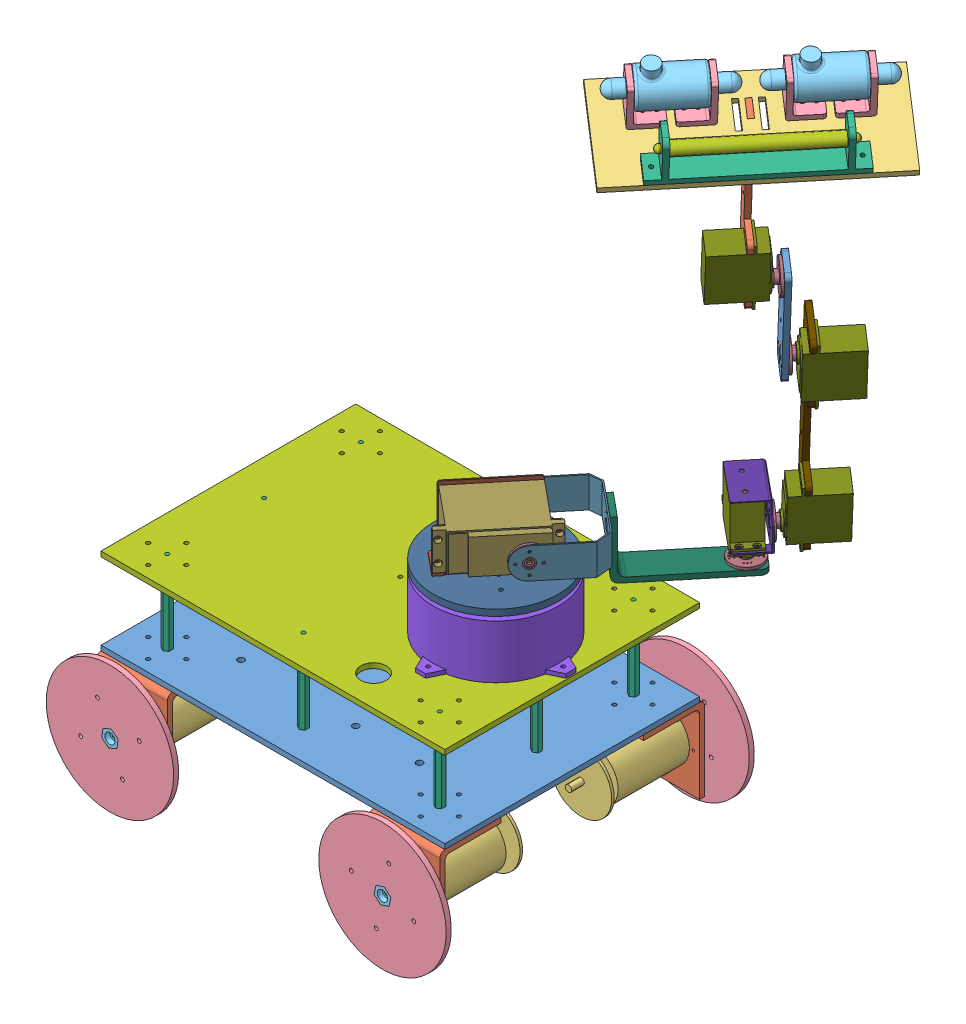
SolidWorks assembly robot_config3, configuration Default. Lengths in mm.
Overall size (478.46 609.43 282.21).
55 component instances, 25 part files, 138 mates.
Components (placement in the parent):
- base_odroid_down_fix-1: base_odroid_down_fix [Default] at (39.4639 122.941 229.7749) x (1 0 0) z (0 -1 0) size (270 200 4)
- link_motor_1_port-1: link_motor_1_port [Default] at (221.3654 112.3394 287.3354) x (0 0 -1) z (1 0 0) size (48 66 56)
- motor_dc_NISCA-1: motor_dc_NISCA [Default] at (244.2642 39.7289 313.6416) x (0 -1 0) z (0 0 -1) size (54 48 92)
- roda_shaft-1: roda_shaft [Default] at (185.8398 121.6563 330.6416) x (-0.980223 0.197896 0) z (0 0 1) size (100 100 4)
- shaft_adapter_5mm-1: shaft_adapter_5mm [Default] at (248.7954 72.9583 317.6416) x (0.980223 -0.197896 0) z (0 0 1) size (12 13.86 17)
- link_motor_1_port-2: link_motor_1_port [Default] at (221.3654 112.3394 139.9479) x (0 0 1) z (-1 0 0) size (48 66 56)
- motor_dc_NISCA-2: motor_dc_NISCA [Default] at (198.4666 39.7289 113.6416) x (0 -1 0) z (0 0 1) size (54 48 92)
- shaft_adapter_5mm-3: shaft_adapter_5mm [Default] at (238.0112 59.5291 109.6416) x (0.404857 -0.91438 0) z (0 0 -1) size (12 13.86 17)
- roda_shaft-2: roda_shaft [Default] at (222.1063 135.748 96.6416) x (0.589448 0.807807 0) z (0 0 -1) size (100 100 4)
- link_motor_1_port-5: link_motor_1_port [Default] at (7.3654 112.3394 287.3354) x (0 0 -1) z (1 0 0) size (48 66 56)
- motor_dc_NISCA-5: motor_dc_NISCA [Default] at (-15.5334 128.1531 313.6416) x (0 1 0) z (0 0 -1) size (54 48 92)
- roda_shaft-5: roda_shaft [Default] at (51.5287 56.8466 334.6416) x (0.393495 -0.919327 0) z (0 0 -1) size (100 100 4)
- shaft_adapter_5mm-6: shaft_adapter_5mm [Default] at (0.8367 112.7577 317.6416) x (-0.393495 0.919327 0) z (0 0 1) size (12 13.86 17)
- link_motor_1_port-6: link_motor_1_port [Default] at (7.3654 112.3394 139.9479) x (0 0 1) z (-1 0 0) size (48 66 56)
- motor_dc_NISCA-6: motor_dc_NISCA [Default] at (-15.5334 39.7289 113.6416) x (0 -1 0) z (0 0 1) size (54 48 92)
- roda_shaft-6: roda_shaft [Default] at (45.258 48.6046 96.6416) x (0.202799 -0.97922 0) z (0 0 -1) size (100 100 4)
- shaft_adapter_5mm-7: shaft_adapter_5mm [Default] at (36.6325 79.8838 109.6416) x (0.949429 -0.313981 0) z (0 0 -1) size (12 13.86 17)
- spacer_6cm-2: spacer_6cm [Default] at (221.7099 182.941 288.7798) x (0.5 0 -0.866025) z (0 -1 0) size (6 6.93 68)
- spacer_6cm-3: spacer_6cm [Default] at (114.7099 182.941 288.7798) x (0.5 0 -0.866025) z (0 -1 0) size (6 6.93 68)
- spacer_6cm-4: spacer_6cm [Default] at (7.7099 182.941 288.7798) x (0.5 0 -0.866025) z (0 -1 0) size (6 6.93 68)
- spacer_6cm-5: spacer_6cm [Default] at (221.7099 182.941 212.7798) x (0.5 0 -0.866025) z (0 -1 0) size (6 6.93 68)
- spacer_6cm-7: spacer_6cm [Default] at (7.7099 182.941 212.7798) x (0.5 0 -0.866025) z (0 -1 0) size (6 6.93 68)
- spacer_6cm-8: spacer_6cm [Default] at (221.7099 182.941 136.7798) x (0.5 0 -0.866025) z (0 -1 0) size (6 6.93 68)
- spacer_6cm-9: spacer_6cm [Default] at (114.7099 182.941 136.7798) x (0.5 0 -0.866025) z (0 -1 0) size (6 6.93 68)
- spacer_6cm-10: spacer_6cm [Default] at (7.7099 182.941 136.7798) x (0.5 0 -0.866025) z (0 -1 0) size (6 6.93 68)
- base_odroid_up_fix-1: base_odroid_up_fix [Default] at (189.2669 186.941 197.5083) x (-1 0 0) z (0 -1 0) size (270 200 4)
- base_arm-1: base_arm [Default] at (189.3654 194.0898 219.4289) x (0 0 1) z (-1 0 0) size (118.01 42 118.01)
- servo_hs422-1: servo_hs422 [Default] at (199.6524 210.6756 203.7356) x (0 0 1) z (-1 0 0) size (19.81 42.14 58.23)
- link1_arm-1: link1_arm [Default] at (172.3903 232.0663 234.1867) x (-0.636951 0 0.770904) z (0 1 0) size (98 98 12)
- bracket_servo_hs755-1: bracket_servo_hs755 [Default] at (243.1616 266.4802 210.0945) x (0.770904 0 0.636951) z (-0.636951 0 0.770904) size (44 34 74)
- servo_hs755-1: servo_hs755 [Default] at (176.5266 211.9363 189.931) x (0 -1 0) z (0.770904 0 0.636951) size (29 74 56.99)
- servo_horn_general-1: servo_horn_general [Default] at (195.7001 253.8913 259.3384) x (-0.636951 0 0.770904) z (-0.770904 0 -0.636951) size (24 24 6)
- link2_ubracket-2: link2_ubracket [Default] at (215.3537 269.0663 164.4418) x (-0.770904 0 -0.636951) z (0 -1 0) size (66 59 24)
- link2_fix-2: link2_fix [Default] at (253.1531 265.014 120.0732) x (0 1 0) z (0.770904 0 0.636951) size (45.14 89 24)
- servo_horn_general-2: servo_horn_general [Default] at (247.2461 229.0663 141.0776) x (-0.636951 0 0.770904) z (0 1 0) size (24 24 6)
- servo_hs645-2: servo_hs645 [Default] at (304.0905 273.4208 144.6257) x (0.770904 0 0.636951) z (0 -1 0) size (53.34 19.56 42.35)
- bracket_servo_645-2: bracket_servo_645 [Default] at (296.9026 227.1529 113.9586) x (0 -1 0) z (-0.770904 0 -0.636951) size (34 24 57)
- servo_horn_general-3: servo_horn_general [Default] at (251.257 260.864 65.7049) x (-0.744637 0.258819 -0.615247) z (0.636951 0 -0.770904) size (24 24 6)
- servo_hs645-3: servo_hs645 [Default] at (316.8702 207.0204 62.3814) x (-0.184952 -0.970794 -0.152815) z (-0.636951 0 0.770904) size (53.34 19.56 42.35)
- link4_fix-1: link4_fix [Default] at (342.5011 442.4647 113.2951) x (0.184952 0.970794 0.152815) z (-0.636951 0 0.770904) size (176.25 35 4)
- servo_hs645-4: servo_hs645 [Default] at (343.1883 434.3652 76.7961) x (0.184952 0.970794 0.152815) z (-0.636951 0 0.770904) size (53.34 19.56 42.35)
- link5_fix-1: link5_fix [Default] at (287.2407 422.6871 88.1057) x (-0.748389 0.239916 -0.618348) z (-0.636951 0 0.770904) size (24 90 4)
- servo_horn_general-4: servo_horn_general [Default] at (310.6357 343.4488 107.4355) x (-0.184952 -0.970794 -0.152815) z (0.636951 0 -0.770904) size (24 24 6)
- servo_horn_general-5: servo_horn_general [Default] at (337.5667 498.1796 134.8756) x (0.184952 0.970794 0.152815) z (-0.636951 0 0.770904) size (24 24 6)
- servo_hs645-5: servo_hs645 [Default] at (280.4728 415.1306 145.2381) x (-0.184952 -0.970794 -0.152815) z (0.636951 0 -0.770904) size (53.34 19.56 42.35)
- link6_eff-1: link6_eff [Default] at (311.3622 416.7967 141.0236) x (-0.184952 -0.970794 -0.152815) z (0.636951 0 -0.770904) size (140.63 35 4)
- base_link_effector_fix-2: base_link_effector_fix [Default] at (314.6552 575.9834 144.6533) x (0.636951 0 -0.770904) z (0.184952 0.970794 0.152815) size (180 80 4)
- base_webcam_fix1-2: base_webcam_fix1 [Default] at (272.2421 579.9584 196.9091) x (0.636951 0 -0.770904) z (0.748389 -0.239916 0.618348) size (23 34 20)
- base_webcam_fix1-3: base_webcam_fix1 [Default] at (319.6943 575.1601 169.96) x (-0.636951 0 0.770904) z (-0.748389 0.239916 -0.618348) size (23 34 20)
- base_webcam_fix1-4: base_webcam_fix1 [Default] at (328.9307 579.9584 128.2986) x (0.636951 0 -0.770904) z (0.748389 -0.239916 0.618348) size (23 34 20)
- base_webcam_fix1-5: base_webcam_fix1 [Default] at (376.3829 575.1601 101.3495) x (-0.636951 0 0.770904) z (-0.748389 0.239916 -0.618348) size (23 34 20)
- webcam_sturdy-3: webcam_sturdy [Default] at (316.8473 600.8583 167.2044) x (0.636951 0 -0.770904) z (0.184952 0.970794 0.152815) size (79 27 33.5)
- webcam_sturdy-4: webcam_sturdy [Default] at (373.5359 600.8583 98.5939) x (0.636951 0 -0.770904) z (0.184952 0.970794 0.152815) size (79 27 33.5)
- base_GM-1: base_GM [Default] at (374.7193 578.0083 139.2381) x (0.636951 0 -0.770904) z (0.748389 -0.239916 0.618348) size (128 34 20)
- tabung_GM-1: tabung_GM [Default] at (417.4802 551.1939 161.2492) x (0.645633 -0.546436 0.533447) z (-0.636951 0 0.770904) size (10 10 116)
Mates (geometry in assembly coordinates):
- Coincident1: coincident anti-aligned: plane of link_motor_1_port-1 through (193.3654 52.941 313.6416) normal (0 0 -1); plane of motor_dc_NISCA-1 through (221.3654 83.941 313.6416) normal (0 0 1)
- Concentric1: concentric aligned: cylinder of link_motor_1_port-1 through (221.3654 83.941 317.6416) axis (0 0 -1) radius 9.5; cylinder of motor_dc_NISCA-1 through (221.3654 83.941 317.6416) axis (0 0 -1) radius 9
- Concentric2: concentric anti-aligned: cylinder of link_motor_1_port-1 through (221.3654 106.941 317.6416) axis (0 0 -1) radius 1; cylinder of motor_dc_NISCA-1 through (221.3654 106.941 311.6416) axis (0 0 1) radius 1.5
- Coincident2: coincident anti-aligned: plane of motor_dc_NISCA-1 through (244.2642 39.7289 317.6416) normal (0 0 1); plane of shaft_adapter_5mm-1 through (221.3654 83.941 317.6416) normal (0 0 -1)
- Concentric4: concentric aligned: cylinder of motor_dc_NISCA-1 through (221.3654 83.941 330.6416) axis (0 0 -1) radius 2.5; cylinder of shaft_adapter_5mm-1 through (221.3654 83.941 330.6416) axis (0 0 -1) radius 2.5
- Coincident3: coincident anti-aligned: plane of roda_shaft-1 through (222.7365 90.7322 330.6416) normal (0.318728 -0.947846 0); plane of shaft_adapter_5mm-1 through (222.7365 90.7322 334.6416) normal (-0.318728 0.947846 0)
- Coincident4: coincident aligned: plane of roda_shaft-1 through (221.3654 83.941 334.6416) normal (0 0 1); plane of shaft_adapter_5mm-1 through (248.7954 72.9583 334.6416) normal (0 0 1)
- Coincident7: coincident anti-aligned: plane of roda_shaft-1 through (214.7985 81.7328 330.6416) normal (0.661495 0.74995 0); plane of shaft_adapter_5mm-1 through (214.7985 81.7328 334.6416) normal (-0.661495 -0.74995 0)
- Coincident8: coincident anti-aligned: plane of link_motor_1_port-2 through (249.3654 52.941 113.6416) normal (0 0 1); plane of motor_dc_NISCA-2 through (221.3654 83.941 113.6416) normal (0 0 -1)
- Concentric5: concentric aligned: cylinder of link_motor_1_port-2 through (221.3654 83.941 109.6416) axis (0 0 1) radius 9.5; cylinder of motor_dc_NISCA-2 through (221.3654 83.941 109.6416) axis (0 0 1) radius 9
- Concentric7: concentric anti-aligned: cylinder of link_motor_1_port-2 through (221.3654 106.941 109.6416) axis (0 0 1) radius 1; cylinder of motor_dc_NISCA-2 through (221.3654 106.941 115.6416) axis (0 0 -1) radius 1.5
- Coincident9: coincident anti-aligned: plane of base_odroid_down_fix-1 through (39.4639 118.941 229.7749) normal (0 -1 0); plane of link_motor_1_port-1 through (193.3654 118.941 269.6416) normal (0 1 0)
- Concentric8: concentric anti-aligned: cylinder of base_odroid_down_fix-1 through (206.3654 118.941 289.6416) axis (0 1 0) radius 1.5; cylinder of link_motor_1_port-1 through (206.3654 118.941 289.6416) axis (0 -1 0) radius 1.5
- Concentric9: concentric anti-aligned: cylinder of base_odroid_down_fix-1 through (236.3654 118.941 289.6416) axis (0 1 0) radius 1.5; cylinder of link_motor_1_port-1 through (236.3654 118.941 289.6416) axis (0 -1 0) radius 1.5
- Coincident11: coincident aligned: plane of shaft_adapter_5mm-3 through (238.0112 59.5291 92.6416) normal (0 0 -1); plane of roda_shaft-2 through (221.3654 83.941 92.6416) normal (0 0 -1)
- Coincident12: coincident anti-aligned: plane of shaft_adapter_5mm-3 through (220.627 77.0523 92.6416) normal (-0.589448 -0.807807 0); plane of roda_shaft-2 through (220.627 77.0523 96.6416) normal (0.589448 0.807807 0)
- Coincident13: coincident anti-aligned: plane of shaft_adapter_5mm-3 through (227.7004 86.746 92.6416) normal (0.994305 -0.106573 0); plane of roda_shaft-2 through (227.7004 86.746 96.6416) normal (-0.994305 0.106573 0)
- Coincident14: coincident anti-aligned: plane of motor_dc_NISCA-2 through (198.4666 39.7289 109.6416) normal (0 0 -1); plane of shaft_adapter_5mm-3 through (221.3654 83.941 109.6416) normal (0 0 1)
- Concentric10: concentric aligned: cylinder of motor_dc_NISCA-2 through (221.3654 83.941 96.6416) axis (0 0 1) radius 2.5; cylinder of shaft_adapter_5mm-3 through (221.3654 83.941 96.6416) axis (0 0 1) radius 2.5
- Coincident15: coincident anti-aligned: plane of base_odroid_down_fix-1 through (39.4639 118.941 229.7749) normal (0 -1 0); plane of link_motor_1_port-2 through (249.3654 118.941 157.6416) normal (0 1 0)
- Concentric11: concentric anti-aligned: cylinder of base_odroid_down_fix-1 through (206.3654 118.941 137.6416) axis (0 1 0) radius 1.5; cylinder of link_motor_1_port-2 through (206.3654 118.941 137.6416) axis (0 -1 0) radius 1.5
- Concentric12: concentric anti-aligned: cylinder of base_odroid_down_fix-1 through (236.3654 118.941 137.6416) axis (0 1 0) radius 1.5; cylinder of link_motor_1_port-2 through (236.3654 118.941 137.6416) axis (0 -1 0) radius 1.5
- Coincident16: coincident anti-aligned: plane of link_motor_1_port-5 through (-20.6346 52.941 313.6416) normal (0 0 -1); plane of motor_dc_NISCA-5 through (7.3654 83.941 313.6416) normal (0 0 1)
- Concentric13: concentric aligned: cylinder of link_motor_1_port-5 through (7.3654 83.941 317.6416) axis (0 0 -1) radius 9.5; cylinder of motor_dc_NISCA-5 through (7.3654 83.941 317.6416) axis (0 0 -1) radius 9
- Concentric14: concentric anti-aligned: cylinder of link_motor_1_port-5 through (7.3654 106.941 317.6416) axis (0 0 -1) radius 1; cylinder of motor_dc_NISCA-5 through (7.3654 106.941 311.6416) axis (0 0 1) radius 1.5
- Concentric16: concentric aligned: cylinder of motor_dc_NISCA-5 through (7.3654 83.941 330.6416) axis (0 0 -1) radius 2.5; cylinder of shaft_adapter_5mm-6 through (7.3654 83.941 330.6416) axis (0 0 -1) radius 2.5
- Coincident17: coincident anti-aligned: plane of motor_dc_NISCA-5 through (-15.5334 128.1531 317.6416) normal (0 0 1); plane of shaft_adapter_5mm-6 through (7.3654 83.941 317.6416) normal (0 0 -1)
- Coincident18: coincident anti-aligned: plane of roda_shaft-5 through (6.5417 77.062 334.6416) normal (0.599413 0.80044 0); plane of shaft_adapter_5mm-6 through (0.9961 81.2148 334.6416) normal (-0.599413 -0.80044 0)
- Coincident19: coincident aligned: plane of roda_shaft-5 through (7.3654 83.941 334.6416) normal (0 0 1); plane of shaft_adapter_5mm-6 through (0.8367 112.7577 334.6416) normal (0 0 1)
- Coincident20: coincident anti-aligned: plane of roda_shaft-5 through (1.8198 88.0939 334.6416) normal (0.393495 -0.919327 0); plane of shaft_adapter_5mm-6 through (8.1891 90.8201 334.6416) normal (-0.393495 0.919327 0)
- Coincident21: coincident anti-aligned: plane of base_odroid_down_fix-1 through (39.4639 118.941 229.7749) normal (0 -1 0); plane of link_motor_1_port-5 through (-20.6346 118.941 269.6416) normal (0 1 0)
- Concentric17: concentric anti-aligned: cylinder of base_odroid_down_fix-1 through (-7.6346 118.941 289.6416) axis (0 1 0) radius 1.5; cylinder of link_motor_1_port-5 through (-7.6346 118.941 289.6416) axis (0 -1 0) radius 1.5
- Concentric18: concentric anti-aligned: cylinder of base_odroid_down_fix-1 through (22.3654 118.941 289.6416) axis (0 1 0) radius 1.5; cylinder of link_motor_1_port-5 through (22.3654 118.941 289.6416) axis (0 -1 0) radius 1.5
- Coincident22: coincident anti-aligned: plane of link_motor_1_port-6 through (35.3654 52.941 113.6416) normal (0 0 1); plane of motor_dc_NISCA-6 through (7.3654 83.941 113.6416) normal (0 0 -1)
- Concentric19: concentric aligned: cylinder of link_motor_1_port-6 through (7.3654 83.941 109.6416) axis (0 0 1) radius 9.5; cylinder of motor_dc_NISCA-6 through (7.3654 83.941 109.6416) axis (0 0 1) radius 9
- Concentric20: concentric anti-aligned: cylinder of link_motor_1_port-6 through (7.3654 106.941 109.6416) axis (0 0 1) radius 1; cylinder of motor_dc_NISCA-6 through (7.3654 106.941 115.6416) axis (0 0 -1) radius 1.5
- Concentric21: concentric aligned: cylinder of motor_dc_NISCA-6 through (7.3654 83.941 96.6416) axis (0 0 1) radius 2.5; cylinder of shaft_adapter_5mm-7 through (7.3654 83.941 96.6416) axis (0 0 1) radius 2.5
- Coincident23: coincident anti-aligned: plane of motor_dc_NISCA-6 through (-15.5334 39.7289 109.6416) normal (0 0 -1); plane of shaft_adapter_5mm-7 through (7.3654 83.941 109.6416) normal (0 0 1)
- Coincident24: coincident aligned: plane of roda_shaft-6 through (7.3654 83.941 92.6416) normal (0 0 -1); plane of shaft_adapter_5mm-7 through (36.6325 79.8838 92.6416) normal (0 0 -1)
- Coincident25: coincident anti-aligned: plane of roda_shaft-6 through (2.7565 89.1138 96.6416) normal (0.202799 -0.97922 0); plane of shaft_adapter_5mm-7 through (2.7565 89.1138 92.6416) normal (-0.202799 0.97922 0)
- Coincident26: coincident anti-aligned: plane of roda_shaft-6 through (5.1901 77.3632 96.6416) normal (0.74663 0.665239 0); plane of shaft_adapter_5mm-7 through (5.1901 77.3632 92.6416) normal (-0.74663 -0.665239 0)
- Coincident27: coincident anti-aligned: plane of base_odroid_down_fix-1 through (39.4639 118.941 229.7749) normal (0 -1 0); plane of link_motor_1_port-6 through (35.3654 118.941 157.6416) normal (0 1 0)
- Concentric22: concentric anti-aligned: cylinder of base_odroid_down_fix-1 through (-7.6346 118.941 137.6416) axis (0 1 0) radius 1.5; cylinder of link_motor_1_port-6 through (-7.6346 118.941 137.6416) axis (0 -1 0) radius 1.5
- Concentric23: concentric anti-aligned: cylinder of base_odroid_down_fix-1 through (22.3654 118.941 137.6416) axis (0 1 0) radius 1.5; cylinder of link_motor_1_port-6 through (22.3654 118.941 137.6416) axis (0 -1 0) radius 1.5
- Concentric24: concentric aligned: cylinder of base_odroid_down_fix-1 through (221.3654 118.941 289.6416) axis (0 1 0) radius 1.5; cylinder of spacer_6cm-2 through (221.3654 118.941 289.6416) axis (0 1 0) radius 1.5
- Coincident28: coincident anti-aligned: plane of base_odroid_down_fix-1 through (39.4639 122.941 229.7749) normal (0 1 0); plane of spacer_6cm-2 through (221.7099 122.941 288.7798) normal (0 -1 0)
- Parallel2: parallel aligned: plane of base_odroid_down_fix-1 through (249.3654 118.941 229.7749) normal (1 0 0); plane of spacer_6cm-2 through (224.3654 122.941 287.9096) normal (1 0 0)
- Concentric25: concentric anti-aligned: cylinder of spacer_6cm-2 through (221.3654 186.941 289.6416) axis (0 -1 0) radius 1.5; cylinder of base_odroid_up_fix-1 through (221.3654 182.941 289.6416) axis (0 1 0) radius 1.5
- Concentric26: concentric anti-aligned: cylinder of spacer_6cm-7 through (7.3654 186.941 213.6416) axis (0 -1 0) radius 1.5; cylinder of base_odroid_up_fix-1 through (7.3654 182.941 213.6416) axis (0 1 0) radius 1.5
- Coincident29: coincident anti-aligned: plane of spacer_6cm-2 through (221.7099 182.941 288.7798) normal (0 1 0); plane of base_odroid_up_fix-1 through (189.2669 182.941 197.5083) normal (0 -1 0)
- Coincident31: coincident anti-aligned: plane of base_arm-1 through (189.3654 225.941 213.6416) normal (0 -1 0); plane of servo_hs422-1 through (199.6524 225.941 203.7356) normal (0 1 0)
- Parallel3: parallel aligned: plane of base_odroid_up_fix-1 through (249.3654 182.941 197.5083) normal (1 0 0); plane of servo_hs422-1 through (219.5914 210.6756 223.5476) normal (1 0 0)
- Coincident33: coincident anti-aligned: plane of base_odroid_up_fix-1 through (189.2669 186.941 197.5083) normal (0 1 0); plane of base_arm-1 through (189.3654 186.941 259.6416) normal (0 -1 0)
- Concentric28: concentric anti-aligned: cylinder of base_odroid_up_fix-1 through (242.3654 182.941 213.6416) axis (0 1 0) radius 1.5; cylinder of base_arm-1 through (242.3654 189.941 213.6416) axis (0 -1 0) radius 1.5
- Concentric29: concentric anti-aligned: cylinder of base_odroid_up_fix-1 through (189.3654 182.941 160.6416) axis (0 1 0) radius 1.5; cylinder of base_arm-1 through (189.3654 189.941 160.6416) axis (0 -1 0) radius 1.5
- Parallel5: parallel aligned: plane of base_odroid_up_fix-1 through (189.2669 182.941 113.6416) normal (0 0 -1); plane of servo_hs422-1 through (199.6524 210.6756 203.7356) normal (0 0 -1)
- Concentric30: concentric aligned: cylinder of base_arm-1 through (189.3654 225.941 213.6416) axis (0 1 0) radius 5.4623; cylinder of servo_hs422-1 through (189.3654 202.0734 213.6416) axis (0 1 0) radius 6.4897
- Concentric31: concentric aligned: cylinder of servo_hs422-1 through (189.3654 212.8107 213.6416) axis (0 1 0) radius 2.8131; cylinder of link1_arm-1 through (189.3654 228.0663 213.6416) axis (0 1 0) radius 3
- Coincident36: coincident anti-aligned: plane of servo_hs422-1 through (199.6524 232.0663 223.5476) normal (0 1 0); plane of link1_arm-1 through (189.3654 232.0663 213.6416) normal (0 -1 0)
- Concentric32: concentric aligned: cylinder of link1_arm-1 through (189.3654 240.0663 213.6416) axis (0 -1 0) radius 4; cylinder of bracket_servo_hs755-1 through (189.3654 238.0663 213.6416) axis (0 -1 0) radius 4
- Coincident38: coincident anti-aligned: plane of link1_arm-1 through (189.3654 237.0663 213.6416) normal (0 1 0); plane of bracket_servo_hs755-1 through (142.6711 237.0663 223.0566) normal (0 -1 0)
- Concentric33: concentric anti-aligned: cylinder of link1_arm-1 through (184.2698 232.0663 219.8089) axis (0 1 0) radius 1.5; cylinder of bracket_servo_hs755-1 through (184.2698 238.0663 219.8089) axis (0 -1 0) radius 1.5
- Coincident40: coincident anti-aligned: plane of bracket_servo_hs755-1 through (176.5909 237.0663 251.0824) normal (0.770904 0 0.636951); plane of servo_hs755-1 through (206.5918 211.9363 214.7721) normal (-0.770904 0 -0.636951)
- Concentric36: concentric aligned: cylinder of bracket_servo_hs755-1 through (177.7308 248.5663 248.1327) axis (0.770904 0 0.636951) radius 1.5; cylinder of servo_hs755-1 through (178.5017 248.5663 248.7697) axis (0.770904 0 0.636951) radius 2.5
- Concentric37: concentric aligned: cylinder of bracket_servo_hs755-1 through (221.0435 264.5663 195.7112) axis (0.770904 0 0.636951) radius 1.5; cylinder of servo_hs755-1 through (221.8144 264.5663 196.3482) axis (0.770904 0 0.636951) radius 2.5
- Concentric39: concentric anti-aligned: cylinder of servo_hs755-1 through (223.8994 257.0663 222.0687) axis (-0.770904 0 -0.636951) radius 3; cylinder of servo_horn_general-1 through (221.5866 257.0663 220.1578) axis (0.770904 0 0.636951) radius 3
- Coincident41: coincident anti-aligned: plane of servo_hs755-1 through (223.8994 257.0663 222.0687) normal (0.770904 0 0.636951); plane of servo_horn_general-1 through (223.8994 257.0663 222.0687) normal (-0.770904 0 -0.636951)
- Concentric40: concentric anti-aligned: cylinder of servo_horn_general-1 through (226.2121 257.0663 223.9795) axis (-0.770904 0 -0.636951) radius 4; cylinder of link2_ubracket-2 through (225.4412 257.0663 223.3426) axis (0.770904 0 0.636951) radius 4
- Coincident42: coincident anti-aligned: plane of servo_horn_general-1 through (225.4412 257.0663 223.3426) normal (0.770904 0 0.636951); plane of link2_ubracket-2 through (249.1176 245.0663 194.6868) normal (-0.770904 0 -0.636951)
- Concentric41: concentric aligned: cylinder of servo_horn_general-1 through (223.8994 265.0663 222.0687) axis (0.770904 0 0.636951) radius 0.5; cylinder of link2_ubracket-2 through (225.4412 265.0663 223.3426) axis (0.770904 0 0.636951) radius 1
- Coincident46: coincident anti-aligned: plane of link2_ubracket-2 through (248.8913 245.0663 181.7506) normal (0.636951 0 -0.770904); plane of link2_fix-2 through (239.6404 265.014 174.1072) normal (-0.636951 0 0.770904)
- Concentric45: concentric anti-aligned: cylinder of link2_ubracket-2 through (229.7526 257.0663 167.2347) axis (0.636951 0 -0.770904) radius 4; cylinder of link2_fix-2 through (232.9374 257.0663 163.3802) axis (-0.636951 0 0.770904) radius 4
- Concentric46: concentric anti-aligned: cylinder of link2_ubracket-2 through (223.5854 257.0663 162.1391) axis (0.636951 0 -0.770904) radius 1; cylinder of link2_fix-2 through (226.7702 257.0663 158.2846) axis (-0.636951 0 0.770904) radius 1.5
- Coincident47: coincident anti-aligned: plane of servo_horn_general-2 through (279.4348 231.0663 107.1041) normal (0 1 0); plane of servo_hs645-2 through (279.4348 231.0663 107.1041) normal (0 -1 0)
- Concentric48: concentric anti-aligned: cylinder of servo_horn_general-2 through (279.4348 234.0663 107.1041) axis (0 -1 0) radius 3; cylinder of servo_hs645-2 through (279.4348 231.0663 107.1041) axis (0 1 0) radius 2.9972
- Coincident48: coincident anti-aligned: plane of link2_fix-2 through (271.6548 229.0663 135.36) normal (0 1 0); plane of servo_horn_general-2 through (279.4348 229.0663 107.1041) normal (0 -1 0)
- Concentric49: concentric anti-aligned: cylinder of link2_fix-2 through (279.4348 229.0663 107.1041) axis (0 -1 0) radius 4; cylinder of servo_horn_general-2 through (279.4348 228.0663 107.1041) axis (0 1 0) radius 4
- Concentric50: concentric aligned: cylinder of link2_fix-2 through (273.2676 229.0663 102.0085) axis (0 -1 0) radius 1.5; cylinder of servo_horn_general-2 through (273.2676 231.0663 102.0085) axis (0 -1 0) radius 0.5
- Coincident50: coincident anti-aligned: plane of servo_hs645-2 through (304.0905 244.8458 144.6257) normal (0 -1 0); plane of bracket_servo_645-2 through (257.4994 244.8458 72.1597) normal (0 1 0)
- Concentric51: concentric aligned: cylinder of servo_hs645-2 through (286.4152 248.0208 119.7908) axis (0 -1 0) radius 2.5019; cylinder of bracket_servo_645-2 through (286.4152 246.3858 119.7908) axis (0 -1 0) radius 1.5
- Concentric52: concentric aligned: cylinder of servo_hs645-2 through (249.2114 248.0208 89.0515) axis (0 -1 0) radius 2.5019; cylinder of bracket_servo_645-2 through (249.2114 246.3858 89.0515) axis (0 -1 0) radius 1.5
- Concentric53: concentric aligned: cylinder of bracket_servo_645-2 through (286.0228 251.8458 95.7269) axis (0.636951 0 -0.770904) radius 4; cylinder of servo_horn_general-3 through (286.0228 251.8458 95.7269) axis (0.636951 0 -0.770904) radius 4
- Coincident51: coincident anti-aligned: plane of bracket_servo_645-2 through (258.1363 273.8458 71.3888) normal (0.636951 0 -0.770904); plane of servo_horn_general-3 through (286.6598 251.8458 94.956) normal (-0.636951 0 0.770904)
- Concentric54: concentric anti-aligned: cylinder of bracket_servo_645-2 through (286.0228 259.8458 95.7269) axis (0.636951 0 -0.770904) radius 1.5; cylinder of servo_horn_general-3 through (287.9337 259.8458 93.4142) axis (-0.636951 0 0.770904) radius 0.5
- Coincident52: coincident anti-aligned: plane of servo_horn_general-3 through (287.9337 251.8458 93.4142) normal (0.636951 0 -0.770904); plane of servo_hs645-3 through (287.9337 251.8458 93.4142) normal (-0.636951 0 0.770904)
- Concentric55: concentric anti-aligned: cylinder of servo_horn_general-3 through (289.8445 251.8458 91.1015) axis (-0.636951 0 0.770904) radius 3; cylinder of servo_hs645-3 through (287.9337 251.8458 93.4142) axis (0.636951 0 -0.770904) radius 2.9972
- Concentric61: concentric anti-aligned: cylinder of servo_hs645-4 through (318.1694 389.5397 111.0658) axis (0.636951 0 -0.770904) radius 2.9972; cylinder of servo_horn_general-4 through (320.0803 389.5397 108.7531) axis (-0.636951 0 0.770904) radius 3
- Coincident56: coincident anti-aligned: plane of servo_hs645-4 through (318.1694 389.5397 111.0658) normal (-0.636951 0 0.770904); plane of servo_horn_general-4 through (318.1694 389.5397 111.0658) normal (0.636951 0 -0.770904)
- Coincident57: coincident anti-aligned: plane of link5_fix-1 through (287.2407 422.6871 88.1057) normal (0.636951 0 -0.770904); plane of servo_horn_general-4 through (316.8955 389.5397 112.6076) normal (-0.636951 0 0.770904)
- Concentric62: concentric anti-aligned: cylinder of link5_fix-1 through (316.8955 389.5397 112.6076) axis (-0.636951 0 0.770904) radius 4; cylinder of servo_horn_general-4 through (316.2586 389.5397 113.3785) axis (0.636951 0 -0.770904) radius 4
- Concentric63: concentric aligned: cylinder of link5_fix-1 through (310.9084 391.4591 107.6608) axis (-0.636951 0 0.770904) radius 1.5; cylinder of servo_horn_general-4 through (312.1823 391.4591 106.119) axis (-0.636951 0 0.770904) radius 0.5
- Concentric64: concentric anti-aligned: cylinder of servo_horn_general-5 through (323.3698 453.6121 129.6315) axis (0.636951 0 -0.770904) radius 3; cylinder of servo_hs645-5 through (325.2807 453.6121 127.3188) axis (-0.636951 0 0.770904) radius 2.9972
- Coincident58: coincident anti-aligned: plane of servo_horn_general-5 through (325.2807 453.6121 127.3188) normal (-0.636951 0 0.770904); plane of servo_hs645-5 through (325.2807 453.6121 127.3188) normal (0.636951 0 -0.770904)
- Coincident59: coincident anti-aligned: plane of link5_fix-1 through (284.6929 422.6871 91.1893) normal (-0.636951 0 0.770904); plane of servo_horn_general-5 through (326.5546 453.6121 125.777) normal (0.636951 0 -0.770904)
- Concentric65: concentric aligned: cylinder of link5_fix-1 through (329.1024 453.6121 122.6934) axis (-0.636951 0 0.770904) radius 4; cylinder of servo_horn_general-5 through (327.1915 453.6121 125.0061) axis (-0.636951 0 0.770904) radius 4
- Concentric66: concentric anti-aligned: cylinder of link5_fix-1 through (335.0895 451.6928 127.6402) axis (-0.636951 0 0.770904) radius 1.5; cylinder of servo_horn_general-5 through (331.2678 451.6928 132.2656) axis (0.636951 0 -0.770904) radius 0.5
- Coincident60: coincident anti-aligned: plane of servo_hs645-5 through (297.622 415.1306 124.4823) normal (-0.636951 0 0.770904); plane of link6_eff-1 through (313.91 416.7967 137.94) normal (0.636951 0 -0.770904)
- Concentric67: concentric aligned: cylinder of servo_hs645-5 through (315.6034 439.3855 141.3161) axis (0.636951 0 -0.770904) radius 2.5019; cylinder of link6_eff-1 through (314.0263 439.3855 143.2248) axis (0.636951 0 -0.770904) radius 1.5
- Concentric68: concentric aligned: cylinder of servo_hs645-5 through (324.5292 486.236 148.6909) axis (0.636951 0 -0.770904) radius 2.5019; cylinder of link6_eff-1 through (322.9521 486.236 150.5997) axis (0.636951 0 -0.770904) radius 1.5
- Coincident61: coincident aligned: plane of link6_eff-1 through (343.4471 571.8335 162.3447) normal (0.184952 0.970794 0.152815); plane of base_link_effector_fix-2 through (315.395 579.8666 145.2645) normal (0.184952 0.970794 0.152815)
- Coincident62: coincident anti-aligned: plane of link6_eff-1 through (313.91 416.7967 137.94) normal (0.636951 0 -0.770904); plane of base_link_effector_fix-2 through (318.4853 575.7154 141.7203) normal (-0.636951 0 0.770904)
- Coincident63: coincident anti-aligned: plane of link6_eff-1 through (289.688 424.5617 117.9269) normal (-0.748389 0.239916 -0.618348); plane of base_link_effector_fix-2 through (315.9375 575.7154 144.8039) normal (0.748389 -0.239916 0.618348)
- Coincident72: coincident anti-aligned: plane of base_link_effector_fix-2 through (315.395 579.8666 145.2645) normal (0.184952 0.970794 0.152815); plane of base_webcam_fix1-2 through (287.2098 575.1601 209.2761) normal (-0.184952 -0.970794 -0.152815)
- Concentric71: concentric anti-aligned: cylinder of base_link_effector_fix-2 through (291.1911 577.5593 189.2163) axis (-0.184952 -0.970794 -0.152815) radius 1.5; cylinder of base_webcam_fix1-2 through (291.1911 577.5593 189.2163) axis (0.184952 0.970794 0.152815) radius 1.5
- Concentric72: concentric anti-aligned: cylinder of base_link_effector_fix-2 through (286.0954 577.5593 195.3836) axis (-0.184952 -0.970794 -0.152815) radius 1.5; cylinder of base_webcam_fix1-2 through (286.0954 577.5593 195.3836) axis (0.184952 0.970794 0.152815) radius 1.5
- Coincident73: coincident anti-aligned: plane of base_link_effector_fix-2 through (315.395 579.8666 145.2645) normal (0.184952 0.970794 0.152815); plane of base_webcam_fix1-3 through (304.7265 579.9584 157.593) normal (-0.184952 -0.970794 -0.152815)
- Concentric73: concentric anti-aligned: cylinder of base_link_effector_fix-2 through (305.8409 577.5593 171.4855) axis (-0.184952 -0.970794 -0.152815) radius 1.5; cylinder of base_webcam_fix1-3 through (305.8409 577.5593 171.4855) axis (0.184952 0.970794 0.152815) radius 1.5
- Concentric74: concentric anti-aligned: cylinder of base_link_effector_fix-2 through (300.7453 577.5593 177.6528) axis (-0.184952 -0.970794 -0.152815) radius 1.5; cylinder of base_webcam_fix1-3 through (300.7453 577.5593 177.6528) axis (0.184952 0.970794 0.152815) radius 1.5
- Coincident74: coincident anti-aligned: plane of base_link_effector_fix-2 through (315.395 579.8666 145.2645) normal (0.184952 0.970794 0.152815); plane of base_webcam_fix1-4 through (343.8985 575.1601 140.6656) normal (-0.184952 -0.970794 -0.152815)
- Concentric75: concentric anti-aligned: cylinder of base_link_effector_fix-2 through (347.8797 577.5593 120.6058) axis (-0.184952 -0.970794 -0.152815) radius 1.5; cylinder of base_webcam_fix1-4 through (347.8797 577.5593 120.6058) axis (0.184952 0.970794 0.152815) radius 1.5
- Concentric76: concentric anti-aligned: cylinder of base_link_effector_fix-2 through (342.7841 577.5593 126.7731) axis (-0.184952 -0.970794 -0.152815) radius 1.5; cylinder of base_webcam_fix1-4 through (342.7841 577.5593 126.7731) axis (0.184952 0.970794 0.152815) radius 1.5
- Coincident75: coincident anti-aligned: plane of base_link_effector_fix-2 through (315.395 579.8666 145.2645) normal (0.184952 0.970794 0.152815); plane of base_webcam_fix1-5 through (361.4152 579.9584 88.9825) normal (-0.184952 -0.970794 -0.152815)
- Concentric77: concentric anti-aligned: cylinder of base_link_effector_fix-2 through (357.4339 577.5593 109.0423) axis (-0.184952 -0.970794 -0.152815) radius 1.5; cylinder of base_webcam_fix1-5 through (357.4339 577.5593 109.0423) axis (0.184952 0.970794 0.152815) radius 1.5
- Concentric78: concentric anti-aligned: cylinder of base_link_effector_fix-2 through (362.5295 577.5593 102.875) axis (-0.184952 -0.970794 -0.152815) radius 1.5; cylinder of base_webcam_fix1-5 through (362.5295 577.5593 102.875) axis (0.184952 0.970794 0.152815) radius 1.5
- Concentric79: concentric anti-aligned: cylinder of base_webcam_fix1-2 through (286.7126 600.8583 203.6765) axis (-0.636951 0 0.770904) radius 6; cylinder of webcam_sturdy-3 through (275.2475 600.8583 217.5528) axis (0.636951 0 -0.770904) radius 6
- Coincident78: coincident anti-aligned: plane of base_webcam_fix1-3 through (302.9185 583.8416 161.2879) normal (-0.636951 0 0.770904); plane of webcam_sturdy-3 through (314.1015 600.8583 170.5277) normal (0.636951 0 -0.770904)
- Parallel8: parallel aligned: plane of base_link_effector_fix-2 through (315.395 579.8666 145.2645) normal (0.184952 0.970794 0.152815); plane of webcam_sturdy-3 through (296.7812 620.2742 199.0238) normal (0.184952 0.970794 0.152815)
- Concentric80: concentric anti-aligned: cylinder of base_webcam_fix1-4 through (343.4012 600.8583 135.066) axis (-0.636951 0 0.770904) radius 6; cylinder of webcam_sturdy-4 through (331.9361 600.8583 148.9423) axis (0.636951 0 -0.770904) radius 6
- Coincident80: coincident anti-aligned: plane of base_webcam_fix1-5 through (359.6072 583.8416 92.6774) normal (-0.636951 0 0.770904); plane of webcam_sturdy-4 through (370.7901 600.8583 101.9172) normal (0.636951 0 -0.770904)
- Parallel9: parallel aligned: plane of base_link_effector_fix-2 through (315.395 579.8666 145.2645) normal (0.184952 0.970794 0.152815); plane of webcam_sturdy-4 through (353.4698 620.2742 130.4133) normal (0.184952 0.970794 0.152815)
- Coincident82: coincident anti-aligned: plane of base_link_effector_fix-2 through (315.395 579.8666 145.2645) normal (0.184952 0.970794 0.152815); plane of base_GM-1 through (328.4592 565.2036 222.6031) normal (-0.184952 -0.970794 -0.152815)
- Concentric81: concentric anti-aligned: cylinder of base_link_effector_fix-2 through (392.9507 567.6028 129.3074) axis (-0.184952 -0.970794 -0.152815) radius 1.5; cylinder of base_GM-1 through (392.9507 567.6028 129.3074) axis (0.184952 0.970794 0.152815) radius 1.5
- Concentric82: concentric anti-aligned: cylinder of base_link_effector_fix-2 through (317.7906 567.6028 220.2741) axis (-0.184952 -0.970794 -0.152815) radius 1.5; cylinder of base_GM-1 through (317.7906 567.6028 220.2741) axis (0.184952 0.970794 0.152815) radius 1.5
- Concentric83: concentric anti-aligned: cylinder of base_GM-1 through (390.7323 586.0478 139.149) axis (0.636951 0 -0.770904) radius 3; cylinder of tabung_GM-1 through (395.8279 586.0478 132.9818) axis (-0.636951 0 0.770904) radius 3
- Coincident83: coincident anti-aligned: plane of base_GM-1 through (337.2954 598.2106 224.7151) normal (0.636951 0 -0.770904); plane of tabung_GM-1 through (327.0372 586.0478 216.2394) normal (-0.636951 0 0.770904)
- LimitAngle1: limit planar angle = 2.451056 rad anti-aligned: plane of servo_hs755-1 through (222.0317 271.0663 202.365) normal (0.636951 0 -0.770904); plane of base_odroid_up_fix-1 through (189.2669 182.941 113.6416) normal (0 0 -1)
- LimitAngle2: limit planar angle = 0 rad aligned: plane of link2_ubracket-2 through (215.3537 269.0663 164.4418) normal (0 1 0); plane of servo_hs755-1 through (222.0317 271.0663 202.365) normal (0 1 0)
- LimitAngle3: limit planar angle = 0 rad aligned: plane of servo_hs645-2 through (249.2534 246.4968 95.1817) normal (-0.770904 0 -0.636951); plane of link2_fix-2 through (253.1531 265.014 120.0732) normal (-0.770904 0 -0.636951)
- LimitAngle4: limit planar angle = 0.242279 rad anti-aligned: plane of link2_fix-2 through (271.6548 229.0663 135.36) normal (0 1 0); plane of link4_fix-1 through (300.1281 233.4265 83.4736) normal (-0.184952 -0.970794 -0.152815)
- Coincident84: coincident anti-aligned: plane of servo_hs645-3 through (299.721 207.0204 83.1372) normal (0.636951 0 -0.770904); plane of link4_fix-1 through (339.9533 442.4647 116.3787) normal (-0.636951 0 0.770904)
- Concentric84: concentric aligned: cylinder of servo_hs645-3 through (292.6313 239.9348 75.3026) axis (-0.636951 0 0.770904) radius 2.5019; cylinder of link4_fix-1 through (294.2084 239.9348 73.3938) axis (-0.636951 0 0.770904) radius 1.5
- Concentric85: concentric aligned: cylinder of servo_hs645-3 through (309.1607 284.3478 88.9598) axis (-0.636951 0 0.770904) radius 2.5019; cylinder of link4_fix-1 through (310.7378 284.3478 87.051) axis (-0.636951 0 0.770904) radius 1.5
- Coincident85: coincident anti-aligned: plane of link4_fix-1 through (342.5011 442.4647 113.2951) normal (0.636951 0 -0.770904); plane of servo_hs645-4 through (324.9875 434.3652 98.8247) normal (-0.636951 0 0.770904)
- Concentric86: concentric aligned: cylinder of link4_fix-1 through (333.0479 401.4507 105.4845) axis (-0.636951 0 0.770904) radius 1.5; cylinder of servo_hs645-4 through (335.0702 401.4507 103.0368) axis (-0.636951 0 0.770904) radius 2.5019
- Concentric87: concentric aligned: cylinder of link4_fix-1 through (316.5184 357.0378 91.8272) axis (-0.636951 0 0.770904) radius 1.5; cylinder of servo_hs645-4 through (318.5408 357.0378 89.3796) axis (-0.636951 0 0.770904) radius 2.5019
- LimitAngle6: limit planar angle = 0.242279 rad anti-aligned: plane of link4_fix-1 through (300.1281 233.4265 83.4736) normal (-0.184952 -0.970794 -0.152815); plane of link2_fix-2 through (271.6548 229.0663 135.36) normal (0 1 0)
- LimitAngle7: limit planar angle = 1.570796 rad anti-aligned: plane of link5_fix-1 through (321.109 375.0112 121.2776) normal (-0.184952 -0.970794 -0.152815); plane of link4_fix-1 through (315.7313 450.2297 96.3656) normal (-0.748389 0.239916 -0.618348)
- LimitAngle8: limit planar angle = 1.570796 rad aligned: plane of link6_eff-1 through (317.438 435.3147 140.855) normal (-0.184952 -0.970794 -0.152815); plane of link5_fix-1 through (303.1476 380.7692 106.4373) normal (-0.748389 0.239916 -0.618348)
